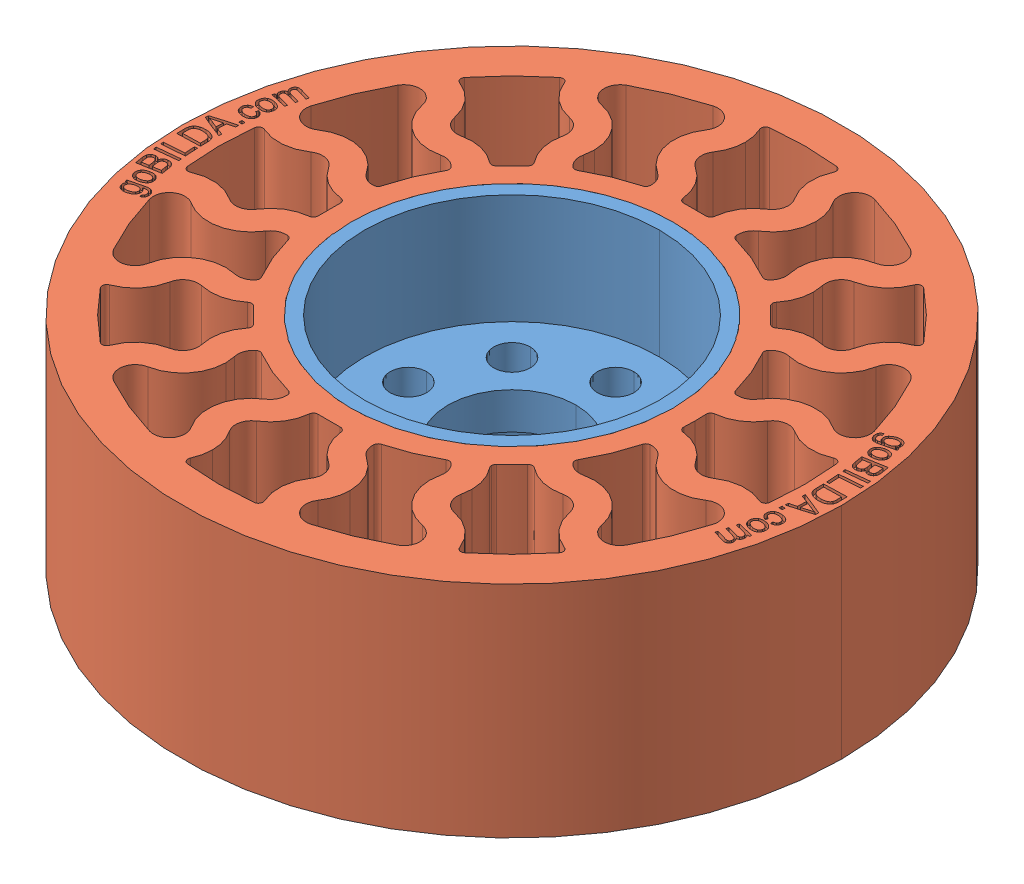
SolidWorks assembly Gecko Wheel 732 OD 613-0014-0072, configuration Default. Lengths in mm.
Overall size (72 24 72).
2 component instances, 2 part files, 0 mates.
Components (placement in the parent):
- 3613-0014-0072 Core.STEP-1: 3613-0014-0072 Core.STEP [Default] at (-50.6425 18.0066 14.4899) size (35.2 24 35.2)
- 3613-0014-0072 Rubber with text.STEP-1: 3613-0014-0072 Rubber with text.STEP [Default] at (-50.6425 18.0066 14.4899) x (0 0 -1) z (1 0 0) size (72 24 72)
